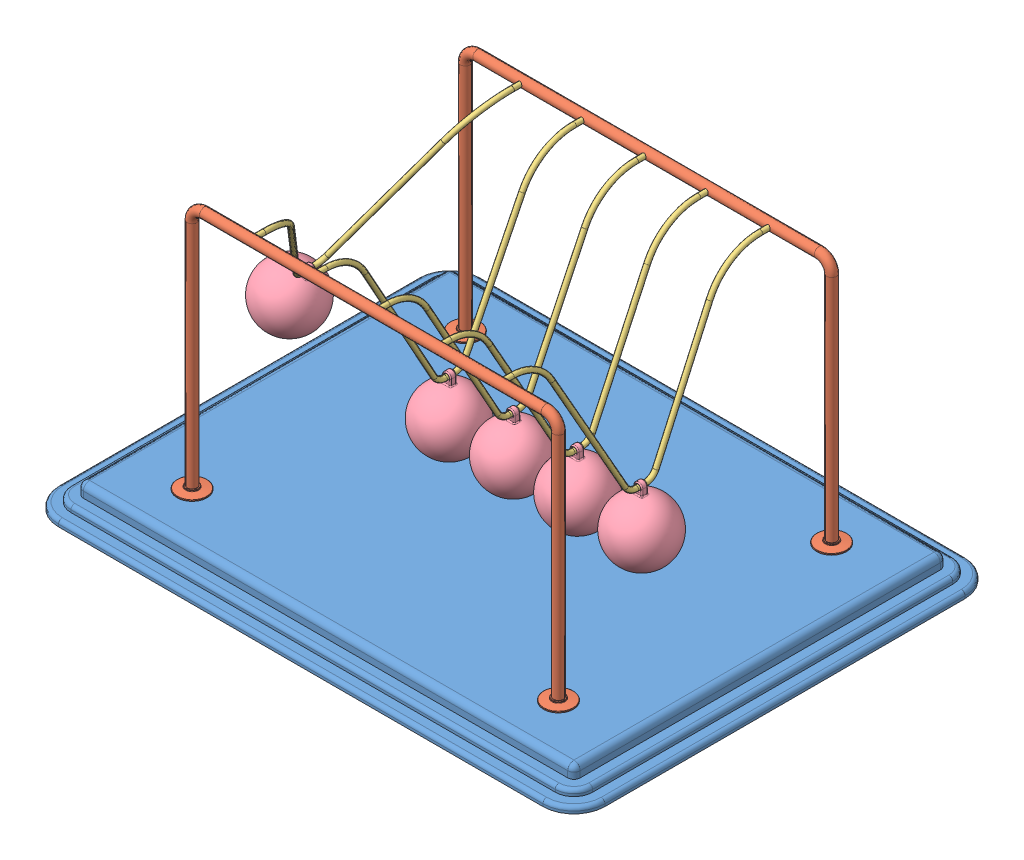
SolidWorks assembly Newtons Cradle NewtonsCradle 0245, configuration Default. Lengths in mm.
Overall size (440 222 340).
13 component instances, 4 part files, 34 mates.
Components (placement in the parent):
- Base 198,541329011345-1: Base 198,541329011345 [Default] at (-16.2968 -4.1587 11.425) size (440 20 340)
- frame NewtonsCradle 0245-1: frame NewtonsCradle 0245 [Default] at (-16.2968 144.4547 -98.575) size (319 202 24)
- frame NewtonsCradle 0245-2: frame NewtonsCradle 0245 [Default] at (-16.2968 144.4547 121.425) x (-1 0 0) z (0 0 -1) size (319 202 24)
- Hanging thing NewtonsCradle 0245-1: Hanging thing NewtonsCradle 0245 [Default] at (-157.6326 134.1825 11.425) x (0 0 1) z (-0.859985 0.510319 0) size (220 129 4)
- Hanging thing NewtonsCradle 0245-2: Hanging thing NewtonsCradle 0245 [Default] at (-66.576 122.8418 11.425) x (0 0 1) z (-0.999994 0.003446 0) size (220 129 4)
- Hanging thing NewtonsCradle 0245-3: Hanging thing NewtonsCradle 0245 [Default] at (-15.6923 122.8436 11.425) x (0 0 1) z (-0.999972 -0.007464 0) size (220 129 4)
- Hanging thing NewtonsCradle 0245-4: Hanging thing NewtonsCradle 0245 [Default] at (35.2213 122.8555 11.425) x (0 0 1) z (-0.999824 -0.018742 0) size (220 129 4)
- Hanging thing NewtonsCradle 0245-5: Hanging thing NewtonsCradle 0245 [Default] at (86.0287 122.8747 11.425) x (0 0 1) z (-0.999588 -0.028711 0) size (220 129 4)
- Sphere NewtonsCradle 0245-1: Sphere NewtonsCradle 0245 [Default] at (-195.3962 70.5436 11.425) x (0.859985 -0.510319 0) z (0 0 1) size (50 58.5 50)
- Sphere NewtonsCradle 0245-2: Sphere NewtonsCradle 0245 [Default] at (88.1533 48.9052 11.425) x (0.999588 0.028711 0) z (0 0 1) size (50 58.5 50)
- Sphere NewtonsCradle 0245-3: Sphere NewtonsCradle 0245 [Default] at (-15.14 48.8456 11.425) x (0.999972 0.007464 0) z (0 0 1) size (50 58.5 50)
- Sphere NewtonsCradle 0245-4: Sphere NewtonsCradle 0245 [Default] at (36.6081 48.8685 11.425) x (0.999824 0.018742 0) z (0 0 1) size (50 58.5 50)
- Sphere NewtonsCradle 0245-5: Sphere NewtonsCradle 0245 [Default] at (-66.831 48.8422 11.425) x (0.999994 -0.003446 0) z (0 0 1) size (50 58.5 50)
Mates (geometry in assembly coordinates):
- Coincident1: coincident anti-aligned: plane of Base-1 through (-211.2968 5.8413 156.425) normal (0 1 0); plane of frame-2 through (-175.7968 5.8413 121.425) normal (0 -1 0)
- Coincident2: coincident anti-aligned: plane of Base-1 through (-211.2968 5.8413 156.425) normal (0 1 0); plane of frame-1 through (143.2032 5.8413 -98.575) normal (0 -1 0)
- Concentric1: concentric anti-aligned: cylinder of frame-1 through (-116.2968 203.8413 -94.575) axis (0 0 -1) radius 2; cylinder of frame-2 through (-116.2968 203.8413 117.425) axis (0 0 1) radius 2
- Concentric2: concentric anti-aligned: cylinder of frame-1 through (83.7032 203.8413 -94.575) axis (0 0 -1) radius 2; cylinder of frame-2 through (83.7032 203.8413 117.425) axis (0 0 1) radius 2
- Distance1: distance = 60 mm: plane of frame-1 through (-16.2968 144.4547 -98.575) normal (0 0 1); line of Base-1 through (-211.2968 -12.1587 -158.575) axis (1 0 0)
- Distance2: distance = 60 mm: line of Base-1 through (178.7032 -12.1587 181.425) axis (-1 0 0); plane of frame-2 through (-16.2968 144.4547 121.425) normal (0 0 -1)
- Distance3: distance = 220 mm: plane of frame-2 through (-16.2968 144.4547 121.425) normal (-1 0 0); line of Base-1 through (-236.2968 -12.1587 156.425) axis (0 0 -1)
- Concentric3: concentric anti-aligned: cylinder of frame-1 through (-116.2968 203.8413 -94.575) axis (0 0 -1) radius 2; cylinder of Hanging thing-1 through (-116.2968 203.8413 111.425) axis (0 0 1) radius 2
- Concentric4: concentric anti-aligned: cylinder of frame-1 through (-116.2968 203.8413 -94.575) axis (0 0 -1) radius 2; cylinder of Hanging thing-1 through (-116.2968 203.8413 -98.575) axis (0 0 1) radius 2
- Concentric5: concentric aligned: cylinder of frame-2 through (-66.2968 203.8413 117.425) axis (0 0 1) radius 2; cylinder of Hanging thing-2 through (-66.2968 203.8413 111.425) axis (0 0 1) radius 2
- Concentric6: concentric aligned: cylinder of frame-2 through (-16.2968 203.8413 117.425) axis (0 0 1) radius 2; cylinder of Hanging thing-3 through (-16.2968 203.8413 111.425) axis (0 0 1) radius 2
- Concentric7: concentric aligned: cylinder of frame-2 through (33.7032 203.8413 117.425) axis (0 0 1) radius 2; cylinder of Hanging thing-4 through (33.7032 203.8413 111.425) axis (0 0 1) radius 2
- Concentric8: concentric aligned: cylinder of frame-2 through (83.7032 203.8413 117.425) axis (0 0 1) radius 2; cylinder of Hanging thing-5 through (83.7032 203.8413 111.425) axis (0 0 1) radius 2
- Coincident5: coincident anti-aligned: plane of frame-2 through (83.7032 203.8413 121.425) normal (0 0 -1); plane of Hanging thing-5 through (83.7032 203.8413 121.425) normal (0 0 1)
- Coincident6: coincident anti-aligned: plane of frame-2 through (33.7032 203.8413 121.425) normal (0 0 -1); plane of Hanging thing-4 through (33.7032 203.8413 121.425) normal (0 0 1)
- Coincident7: coincident anti-aligned: plane of frame-2 through (-16.2968 203.8413 121.425) normal (0 0 -1); plane of Hanging thing-3 through (-16.2968 203.8413 121.425) normal (0 0 1)
- Coincident8: coincident anti-aligned: plane of frame-2 through (-66.2968 203.8413 121.425) normal (0 0 -1); plane of Hanging thing-2 through (-66.2968 203.8413 121.425) normal (0 0 1)
- Coincident9: coincident anti-aligned: plane of frame-2 through (-116.2968 203.8413 121.425) normal (0 0 -1); plane of Hanging thing-1 through (-116.2968 203.8413 121.425) normal (0 0 1)
- Concentric9: concentric anti-aligned: cylinder of Hanging thing-1 through (-117.0163 78.8434 7.925) axis (0 0 1) radius 2; cylinder of Sphere-1 through (-117.0163 78.8434 13.925) axis (0 0 -1) radius 2
- Concentric13: concentric anti-aligned: cylinder of Hanging thing-2 through (-66.7276 78.842 7.925) axis (0 0 1) radius 2; cylinder of Sphere-5 through (-66.7276 78.842 13.925) axis (0 0 -1) radius 2
- Concentric15: concentric anti-aligned: cylinder of Hanging thing-3 through (-15.3639 78.8448 7.925) axis (0 0 1) radius 2; cylinder of Sphere-3 through (-15.3639 78.8448 13.925) axis (0 0 -1) radius 2
- Concentric16: concentric anti-aligned: cylinder of Hanging thing-5 through (87.292 78.8928 7.925) axis (0 0 1) radius 2; cylinder of Sphere-2 through (87.292 78.8928 13.925) axis (0 0 -1) radius 2
- Concentric17: concentric anti-aligned: cylinder of Hanging thing-4 through (36.0459 78.8632 7.925) axis (0 0 1) radius 2; cylinder of Sphere-4 through (36.0459 78.8632 13.925) axis (0 0 -1) radius 2
- Parallel1: parallel anti-aligned: plane of Hanging thing-1; plane of Sphere-1
- Coincident22: coincident anti-aligned: plane of Hanging thing-1; plane of Sphere-1
- Coincident12: coincident aligned: plane of Hanging thing-2 through (-66.576 122.8418 11.425) normal (0 0 1); plane of Sphere-5 through (-66.831 48.8422 11.425) normal (0 0 1)
- Coincident10: coincident aligned: plane of Hanging thing-1 through (-116.763 122.8426 11.425) normal (0 0 1); plane of Sphere-1 through (-118.5806 48.8842 11.425) normal (0 0 1)
- Coincident13: coincident anti-aligned: plane of Hanging thing-2 through (-66.576 122.8418 11.425) normal (-0.999994 0.003446 0); plane of Sphere-5 through (-66.831 48.8422 11.425) normal (0.999994 -0.003446 0)
- Coincident14: coincident anti-aligned: plane of Hanging thing-3 through (-15.6923 122.8436 11.425) normal (-0.999972 -0.007464 0); plane of Sphere-3 through (-15.14 48.8456 11.425) normal (0.999972 0.007464 0)
- Coincident15: coincident aligned: plane of Hanging thing-3 through (-15.6923 122.8436 11.425) normal (0 0 1); plane of Sphere-3 through (-15.14 48.8456 11.425) normal (0 0 1)
- Coincident18: coincident aligned: plane of Hanging thing-4 through (35.2213 122.8555 11.425) normal (0 0 1); plane of Sphere-4 through (36.6081 48.8685 11.425) normal (0 0 1)
- Coincident19: coincident anti-aligned: plane of Hanging thing-4 through (35.2213 122.8555 11.425) normal (-0.999824 -0.018742 0); plane of Sphere-4 through (36.6081 48.8685 11.425) normal (0.999824 0.018742 0)
- Coincident20: coincident anti-aligned: plane of Hanging thing-5 through (86.0287 122.8747 11.425) normal (-0.999588 -0.028711 0); plane of Sphere-2 through (88.1533 48.9052 11.425) normal (0.999588 0.028711 0)
- Coincident21: coincident aligned: plane of Hanging thing-5 through (86.0287 122.8747 11.425) normal (0 0 1); plane of Sphere-2 through (88.1533 48.9052 11.425) normal (0 0 1)
